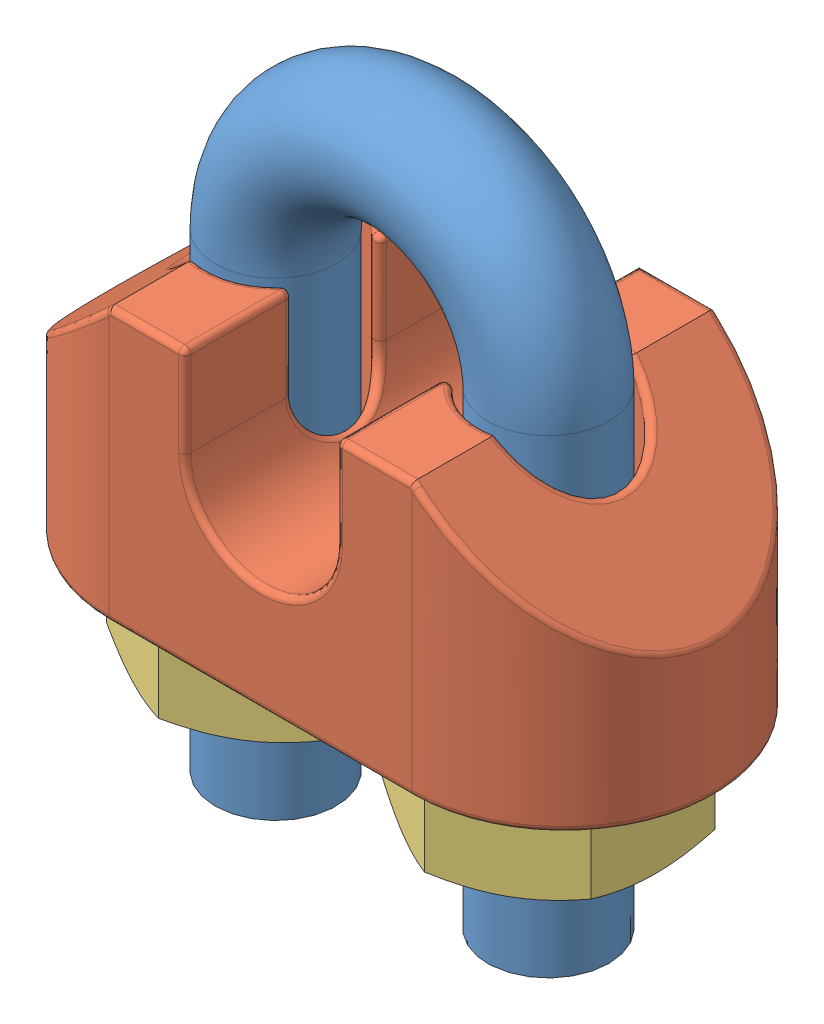
SolidWorks assembly Presilha-Assembly, configuration Valor predeterminado. Lengths in mm.
Overall size (20 22 10).
4 component instances, 3 part files, 5 mates.
Components (placement in the parent):
- Presilha-1: Presilha [Valor predeterminado] at (-8.04 -17.1088 22) size (13 22 4)
- PresilhaHousing-1: PresilhaHousing [Valor predeterminado] at (-8.54 -10.6088 27) size (20 9.01 10)
- hex nut style 1_am-1: hex nut style 1_am [B18.2.4.1M - Hex nut, Style 1,  M4 x 0.7 --D-N] at (0.96 -10.6088 22) x (0.999926 0 0.012193) z (0 1 0) size (7 8.08 3.2)
- hex nut style 1_am-2: hex nut style 1_am [B18.2.4.1M - Hex nut, Style 1,  M4 x 0.7 --D-N] at (-8.04 -13.8088 22) x (0.999136 0 -0.041557) z (0 -1 0) size (7 8.08 3.2)
Mates (geometry in assembly coordinates):
- Concentric1: concentric: cylinder of Presilha-1 through (-8.04 -17.1088 22) axis (0 1 0) radius 2; cylinder of PresilhaHousing-1 through (-8.04 -10.6088 22) axis (0 1 0) radius 2.25
- Concentric2: concentric: cylinder of Presilha-1 through (0.96 -1.6088 22) axis (0 -1 0) radius 2; cylinder of PresilhaHousing-1 through (0.96 -10.6088 22) axis (0 1 0) radius 2.25
- Concentric3: concentric: cylinder of Presilha-1 through (0.96 -1.6088 22) axis (0 -1 0) radius 2; cylinder of hex nut style 1_am-1 through (0.96 -13.8088 22) axis (0 1 0) radius 1.65
- Concentric4: concentric: cylinder of Presilha-1 through (-8.04 -17.1088 22) axis (0 1 0) radius 2; cylinder of hex nut style 1_am-2 through (-8.04 -10.6088 22) axis (0 -1 0) radius 1.65
- Coincident1: coincident: circle of Presilha-1; plane of PresilhaHousing-1 through (-8.54 -1.6088 22) normal (0 1 0)
